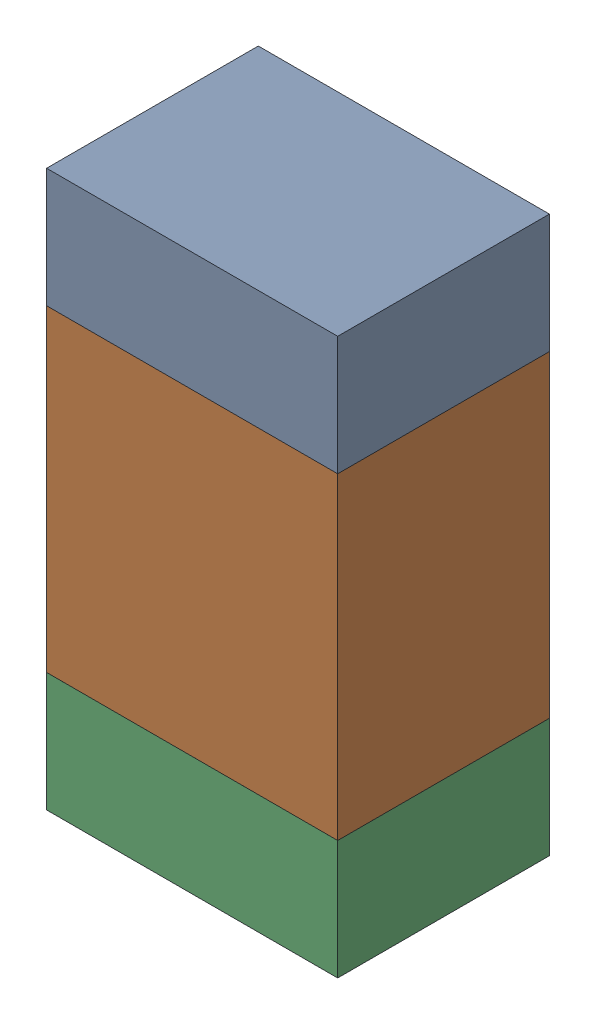
SolidWorks assembly R313_1PCB, configuration Default. Lengths in mm.
Overall size (0.55 1.05 0.4).
6 component instances, 2 part files, 0 mates.
Components (placement in the parent):
- 846483288-1: 846483288 [Default] at (127.6001 109.0124 -2.0638) size (0.55 0.22 0.4)
  - Extruded_12-1: Extruded_12 [Default] at origin size (0.55 0.22 0.4)
- 846483424-1: 846483424 [Default] at (127.6001 108.5999 -2.0638) size (0.55 0.6 0.4)
  - Extruded_13-1: Extruded_13 [Default] at origin size (0.55 0.6 0.4)
- 846483288-2: 846483288 [Default] at (127.6001 108.1874 -2.0638) size (0.55 0.22 0.4)
  - Extruded_12-1: Extruded_12 [Default] at origin size (0.55 0.22 0.4)
